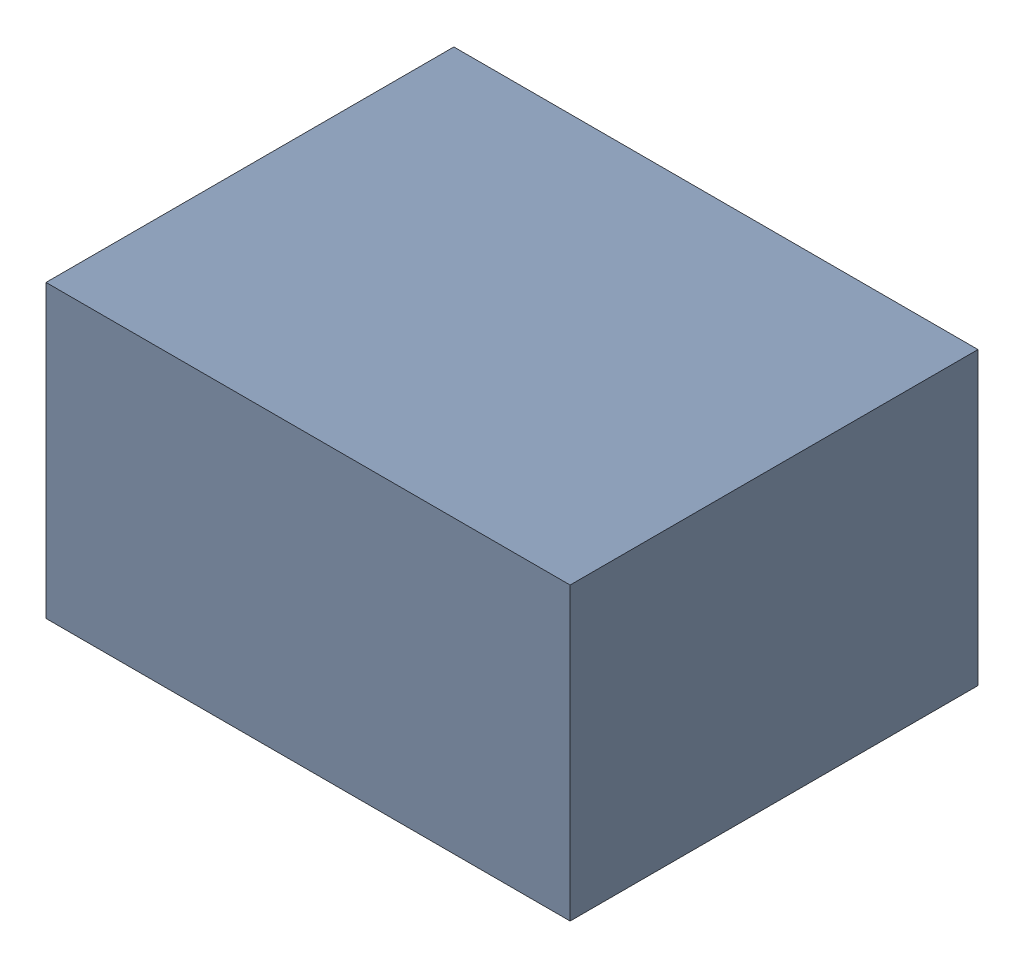
SolidWorks assembly C43, configuration Default. Lengths in mm.
Overall size (1.8 1 1.4).
3 component instances, 2 part files, 0 mates.
Components (placement in the parent):
- 1088884976-1: 1088884976 [Default] at (6.6 17.325 -3.044) size (1.8 1 1.4)
  - Extruded-47-1: Extruded-47 [Default] at origin size (1.8 1 1.4)
- C0603-1: C0603 [Default] at (5.8 17.7251 -1.644) x (1 0 0) z (0 1 0) size (1.6 0.5 0.8)
